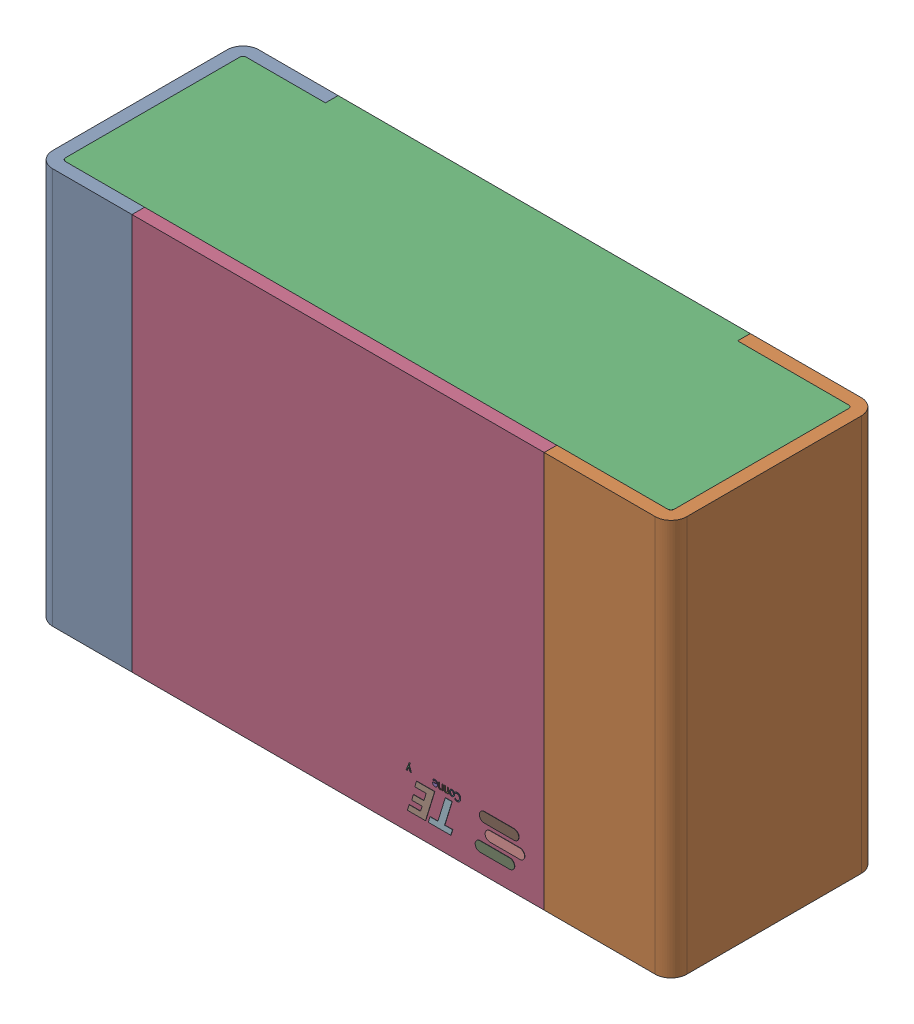
SolidWorks assembly RLL2.step, configuration Default. Lengths in mm.
Overall size (2 1.25 0.65).
5 component instances, 4 part files, 0 mates.
Components (placement in the parent):
- Res_TE_Connectivity_CPF0805B66R5E1_eec.step-1: Res_TE_Connectivity_CPF0805B66R5E1_eec.step [Default] at (10.287 24.257 0) x (-1 0 0) z (0 0 1) size (2 1.25 0.65)
  - 1.step-1: 1.step [Default] at origin size (2 1.25 0.65)
  - 2.step-1: 2.step [Default] at origin size (1.92 1.25 0.61)
  - 3.step-1: 3.step [Default] at origin size (1.3 1.25 0.04)
  - TE connectivity Logo 1 (2).step-1: TE connectivity Logo 1 (2).step [Default] at (5.4285 0.313 0.551) x (-1 0 0) z (0 0 1) size (0.37 0.13 0.11)
